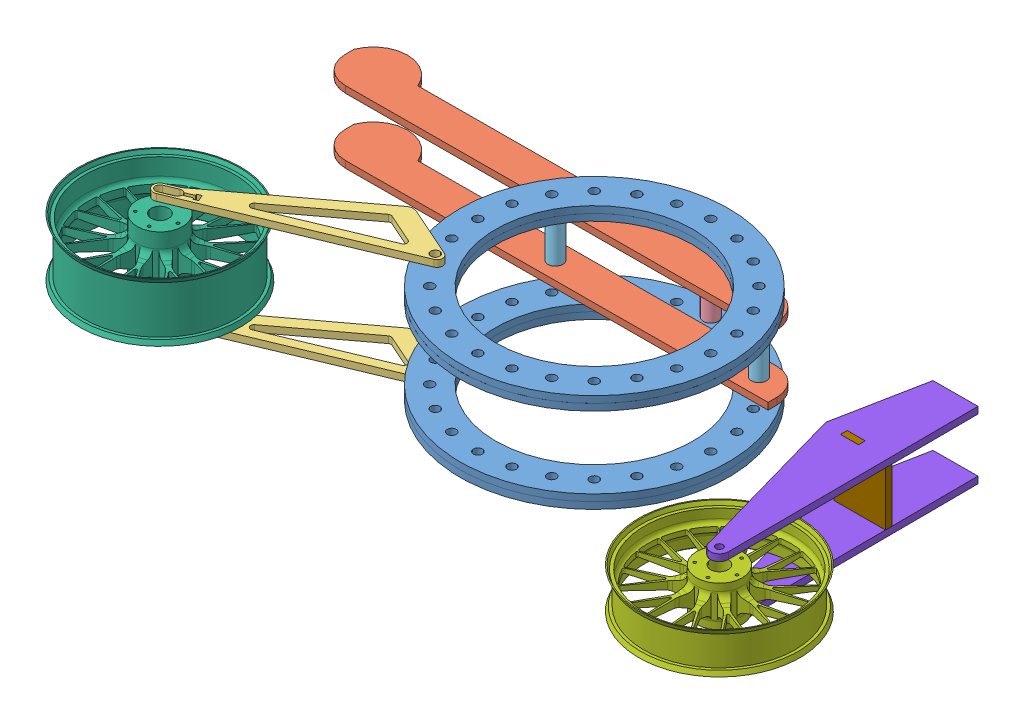
SolidWorks assembly bike, configuration Default. Lengths in mm.
Overall size (2078.57 317.5 1119.66).
16 component instances, 9 part files, 39 mates.
Components (placement in the parent):
- circle-1: circle [Default] at (127.9797 589.8404 731.4492) size (762 19.05 762)
- seat-1: seat [Default] at (-197.3278 570.7904 500.5155) x (0.99999 0 -0.004569) z (0.004569 0 0.99999) size (1270 19.05 162.92)
- swingarm-1: swingarm [Default] at (-157.9818 627.9404 896.5492) x (0.922641 0 -0.385661) z (0.385661 0 0.922641) size (636.92 19.05 149.55)
- swingarm-2: swingarm [Default] at (-157.9818 329.4904 896.5492) x (0.922641 0 -0.385661) z (0.385661 0 0.922641) size (636.92 19.05 149.55)
- circle-2: circle [Default] at (127.9797 348.5404 731.4492) size (762 19.05 762)
- circle-3: circle [Default] at (127.9797 608.8904 731.4492) x (0.965926 0 -0.258819) z (0.258819 0 0.965926) size (762 19.05 762)
- circle-4: circle [Default] at (127.9797 367.5904 731.4492) size (762 19.05 762)
- seat-2: seat [Default] at (-197.3278 386.6404 500.5155) x (0.99999 0 -0.004569) z (0.004569 0 0.99999) size (1270 19.05 162.92)
- 8inch-1: 8inch [Default] at (127.9797 386.6404 401.2492) x (0 1 0) z (0 0 1) size (203.2 42.33 42.33)
- 6.5inch-1: 6.5inch [Default] at (361.4664 570.7904 497.9626) x (0 -1 0) z (0 0 1) size (165.1 42.33 42.33)
- 6.5inch-2: 6.5inch [Default] at (-213.2676 570.7904 500.5884) x (0 -1 0) z (0 0 1) size (165.1 42.33 42.33)
- Wheel Rear-1: Wheel Rear [Default] at (-708.7061 503.3292 1126.7501) x (0.999693 0 -0.024785) z (0 -1 0) size (457.2 457.2 165.1)
- Wheel Front-1: Wheel Front [Default] at (907.0716 488.2404 1155.8767) x (1 0 0) z (0 1 0) size (457.2 457.2 114.3)
- upright-1: upright [Default] at (907.0716 418.3904 1155.8767) x (-0.99999 0 0.004569) z (0.004569 0 0.99999) size (177.8 19.05 736.6)
- upright-2: upright [Default] at (907.0716 589.8404 1155.8767) x (-0.99999 0 0.004569) z (0.004569 0 0.99999) size (177.8 19.05 736.6)
- front_bottom_horizontal-1: front_bottom_horizontal [Default] at (930.426 570.7904 708.0904) x (0 -1 0) z (0.99999 0 -0.004569) size (190.5 19.05 146.05)
Mates (geometry in assembly coordinates):
- Concentric1: concentric anti-aligned: cylinder of circle-1 through (361.4664 608.8904 497.9626) axis (0 1 0) radius 12.7; cylinder of seat-1 through (361.4664 589.8404 497.9626) axis (0 -1 0) radius 12.7
- Coincident1: coincident anti-aligned: plane of circle-1 through (127.9797 589.8404 731.4492) normal (0 -1 0); plane of seat-1 through (-742.2197 589.8404 487.8369) normal (0 1 0)
- Concentric3: concentric anti-aligned: cylinder of circle-1 through (-157.9818 608.8904 896.5492) axis (0 1 0) radius 12.7; cylinder of swingarm-1 through (-157.9818 646.9904 896.5492) axis (0 -1 0) radius 12.7
- Concentric4: concentric aligned: cylinder of circle-1 through (446.9285 608.8904 645.9872) axis (0 1 0) radius 12.7; cylinder of circle-3 through (446.9285 627.9404 645.9872) axis (0 1 0) radius 12.7
- Coincident3: coincident anti-aligned: plane of circle-1 through (127.9797 608.8904 731.4492) normal (0 1 0); plane of circle-3 through (127.9797 608.8904 731.4492) normal (0 -1 0)
- Concentric5: concentric aligned: cylinder of circle-1 through (127.9797 608.8904 1061.6492) axis (0 1 0) radius 12.7; cylinder of circle-3 through (127.9797 627.9404 1061.6492) axis (0 1 0) radius 12.7
- Coincident4: coincident anti-aligned: plane of swingarm-1 through (-152.0576 627.9404 897.5141) normal (0 -1 0); plane of circle-3 through (127.9797 627.9404 731.4492) normal (0 1 0)
- Concentric6: concentric aligned: cylinder of seat-1 through (361.4664 589.8404 497.9626) axis (0 -1 0) radius 12.7; cylinder of seat-2 through (361.4664 405.6904 497.9626) axis (0 -1 0) radius 12.7
- Coincident5: coincident anti-aligned: plane of circle-2 through (127.9797 367.5904 731.4492) normal (0 1 0); plane of circle-4 through (127.9797 367.5904 731.4492) normal (0 -1 0)
- Concentric7: concentric aligned: cylinder of circle-2 through (127.9797 367.5904 401.2492) axis (0 1 0) radius 12.7; cylinder of circle-4 through (127.9797 386.6404 401.2492) axis (0 1 0) radius 12.7
- Concentric8: concentric aligned: cylinder of circle-2 through (361.4664 367.5904 497.9626) axis (0 1 0) radius 12.7; cylinder of circle-4 through (361.4664 386.6404 497.9626) axis (0 1 0) radius 12.7
- Concentric9: concentric aligned: cylinder of circle-3 through (361.4664 627.9404 497.9626) axis (0 1 0) radius 12.7; cylinder of circle-4 through (361.4664 386.6404 497.9626) axis (0 1 0) radius 12.7
- Coincident6: coincident anti-aligned: plane of circle-1 through (127.9797 589.8404 731.4492) normal (0 -1 0); plane of 8inch-1 through (115.2797 589.8404 401.2492) normal (0 1 0)
- Concentric10: concentric anti-aligned: cylinder of circle-1 through (127.9797 608.8904 401.2492) axis (0 1 0) radius 12.7; cylinder of 8inch-1 through (127.9797 386.6404 401.2492) axis (0 -1 0) radius 12.7
- Concentric11: concentric anti-aligned: cylinder of circle-4 through (127.9797 386.6404 401.2492) axis (0 1 0) radius 12.7; cylinder of 8inch-1 through (127.9797 386.6404 401.2492) axis (0 -1 0) radius 12.7
- Coincident7: coincident anti-aligned: plane of circle-4 through (127.9797 386.6404 731.4492) normal (0 1 0); plane of 8inch-1 through (115.2797 386.6404 401.2492) normal (0 -1 0)
- Coincident8: coincident anti-aligned: plane of circle-4 through (127.9797 386.6404 731.4492) normal (0 1 0); plane of seat-2 through (-742.2197 386.6404 487.8369) normal (0 -1 0)
- Coincident9: coincident anti-aligned: plane of seat-2 through (-742.2197 405.6904 487.8369) normal (0 1 0); plane of 6.5inch-1 through (374.1664 405.6904 497.9626) normal (0 -1 0)
- Concentric12: concentric anti-aligned: cylinder of seat-2 through (361.4664 405.6904 497.9626) axis (0 -1 0) radius 12.7; cylinder of 6.5inch-1 through (361.4664 570.7904 497.9626) axis (0 1 0) radius 12.7
- Coincident10: coincident anti-aligned: plane of seat-2 through (-742.2197 405.6904 487.8369) normal (0 1 0); plane of 6.5inch-2 through (-200.5676 405.6904 500.5884) normal (0 -1 0)
- Concentric13: concentric anti-aligned: cylinder of seat-1 through (-213.2676 589.8404 500.5884) axis (0 -1 0) radius 12.7; cylinder of 6.5inch-2 through (-213.2676 570.7904 500.5884) axis (0 1 0) radius 12.7
- Concentric14: concentric anti-aligned: cylinder of seat-2 through (-213.2676 405.6904 500.5884) axis (0 -1 0) radius 12.7; cylinder of 6.5inch-2 through (-213.2676 570.7904 500.5884) axis (0 1 0) radius 21.1667
- Coincident11: coincident anti-aligned: plane of swingarm-2 through (-152.0576 348.5404 897.5141) normal (0 1 0); plane of circle-2 through (127.9797 348.5404 731.4492) normal (0 -1 0)
- Concentric15: concentric anti-aligned: cylinder of swingarm-2 through (-157.9818 348.5404 896.5492) axis (0 -1 0) radius 12.7; cylinder of circle-2 through (-157.9818 367.5904 896.5492) axis (0 1 0) radius 12.7
- Concentric16: concentric aligned: cylinder of swingarm-1 through (-708.7061 646.9904 1126.7501) axis (0 -1 0) radius 19.05; cylinder of swingarm-2 through (-708.7061 348.5404 1126.7501) axis (0 -1 0) radius 19.05
- Concentric18: concentric anti-aligned: cylinder of swingarm-1 through (-708.7061 646.9904 1126.7501) axis (0 -1 0) radius 12.7; cylinder of Wheel Rear-1 through (-708.7061 420.7792 1126.7501) axis (0 1 0) radius 25
- Parallel1: parallel anti-aligned: plane of circle-3 through (127.9797 627.9404 731.4492) normal (0 1 0); plane of Wheel Front-1 through (907.0716 431.0904 1155.8767) normal (0 -1 0)
- Coincident14: coincident anti-aligned: plane of upright-1 through (854.2268 399.3404 708.4385) normal (-0.004569 0 -0.99999); plane of front_bottom_horizontal-1 through (930.426 570.7904 708.0904) normal (0.004569 0 0.99999)
- Parallel2: parallel anti-aligned: plane of Wheel Front-1 through (907.0716 431.0904 1155.8767) normal (0 -1 0); plane of upright-1 through (907.0716 418.3904 1155.8767) normal (0 1 0)
- Coincident16: coincident anti-aligned: plane of upright-1 through (854.2268 399.3404 708.4385) normal (-0.99999 0 0.004569); plane of front_bottom_horizontal-1 through (854.1398 418.3904 689.3887) normal (0.99999 0 -0.004569)
- Coincident17: coincident anti-aligned: plane of upright-1 through (907.0716 418.3904 1155.8767) normal (0 1 0); plane of front_bottom_horizontal-1 through (930.339 418.3904 689.0406) normal (0 -1 0)
- Coincident19: coincident anti-aligned: plane of upright-2 through (854.2268 570.7904 708.4385) normal (-0.004569 0 -0.99999); plane of front_bottom_horizontal-1 through (930.426 570.7904 708.0904) normal (0.004569 0 0.99999)
- Concentric19: concentric anti-aligned: cylinder of Wheel Front-1 through (907.0716 545.3904 1155.8767) axis (0 -1 0) radius 25; cylinder of upright-1 through (907.0716 399.3404 1155.8767) axis (0 1 0) radius 10
- Coincident22: coincident anti-aligned: plane of upright-2 through (854.2268 570.7904 708.4385) normal (-0.004569 0 -0.99999); plane of front_bottom_horizontal-1 through (930.426 570.7904 708.0904) normal (0.004569 0 0.99999)
- Coincident23: coincident anti-aligned: plane of upright-2 through (803.4274 570.7904 708.6706) normal (0.99999 0 -0.004569); plane of front_bottom_horizontal-1 through (803.3403 570.7904 689.6208) normal (-0.99999 0 0.004569)
- Coincident24: coincident anti-aligned: plane of upright-2 through (907.0716 570.7904 1155.8767) normal (0 -1 0); plane of front_bottom_horizontal-1 through (784.2905 570.7904 689.7078) normal (0 1 0)
- Distance1: distance = 25.4 mm anti-aligned: plane of Wheel Front-1 through (907.0716 545.3904 1155.8767) normal (0 1 0); plane of upright-2 through (907.0716 570.7904 1155.8767) normal (0 -1 0)
- Coincident27: coincident aligned: plane of seat-2 through (-652.2117 405.6904 451.7932) normal (-0.004569 0 -0.99999); plane of upright-2 through (929.2221 570.7904 444.5681) normal (-0.004569 0 -0.99999)
- Coincident28: coincident anti-aligned: plane of circle-1 through (127.9797 589.8404 731.4492) normal (0 -1 0); plane of upright-2 through (907.0716 589.8404 1155.8767) normal (0 1 0)
